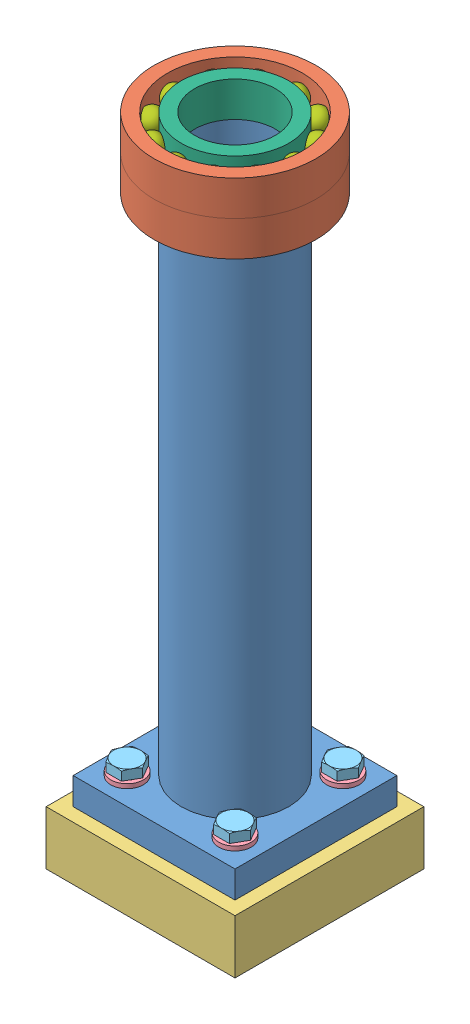
SolidWorks assembly BE101-01Z-02Z 立柱套装, configuration 默认. Lengths in mm.
Overall size (70 243 70).
27 component instances, 7 part files, 12 mates.
Components (placement in the parent):
- BE101-01Z-04Z 烟囱与圈-1: BE101-01Z-04Z 烟囱与圈 [默认] at origin size (60 210 60)
  - BE101-01Z-004 中空立柱-1: BE101-01Z-004 中空立柱 [默认] at origin size (60 210 60)
  - BE101-01Z-006 轴承外圈-1: BE101-01Z-006 轴承外圈 [默认] at (0 193.5 0) size (60 13 60)
- BE101-01Z-005 四眼小板-1: BE101-01Z-005 四眼小板 [默认] at (0 -30 0) size (70 20 70)
- plain washers--product grade c gb-1: plain washers--product grade c gb [GB_FASTENER_WASHER_SMWC 6] at (20 1.6 -20) x (1 0 0) z (0 1 0) size (12 12 1.6)
- hex head bolts-full thread grade c gb-1: hex head bolts-full thread grade c gb [GB_FASTENER_BOLT_HHBFTC M6X20-N] at (20 5.6 -20) x (0 -1 0) z (0 0 1) size (24 11.55 10)
- plain washers--product grade c gb-2: plain washers--product grade c gb [GB_FASTENER_WASHER_SMWC 6] at (20 1.6 20) x (1 0 0) z (0 1 0) size (12 12 1.6)
- plain washers--product grade c gb-3: plain washers--product grade c gb [GB_FASTENER_WASHER_SMWC 6] at (-20 1.6 20) x (1 0 0) z (0 1 0) size (12 12 1.6)
- plain washers--product grade c gb-4: plain washers--product grade c gb [GB_FASTENER_WASHER_SMWC 6] at (-20 1.6 -20) x (1 0 0) z (0 1 0) size (12 12 1.6)
- hex head bolts-full thread grade c gb-2: hex head bolts-full thread grade c gb [GB_FASTENER_BOLT_HHBFTC M6X20-N] at (20 5.6 20) x (0 -1 0) z (0 0 1) size (24 11.55 10)
- hex head bolts-full thread grade c gb-3: hex head bolts-full thread grade c gb [GB_FASTENER_BOLT_HHBFTC M6X20-N] at (-20 5.6 20) x (0 -1 0) z (0 0 1) size (24 11.55 10)
- hex head bolts-full thread grade c gb-4: hex head bolts-full thread grade c gb [GB_FASTENER_BOLT_HHBFTC M6X20-N] at (-20 5.6 -20) x (0 -1 0) z (0 0 1) size (24 11.55 10)
- BE101-01Z-03Z 滚珠轴承-1: BE101-01Z-03Z 滚珠轴承 [默认] at (0 206.5 0) size (60 13 60)
  - BE101-01Z-007 轴承内圈-1: BE101-01Z-007 轴承内圈 [默认] at origin size (40 13 40)
  - BE101-01Z-006 轴承外圈-1: BE101-01Z-006 轴承外圈 [默认] at origin size (60 13 60)
  - BE101-01Z-008 轴承滚珠-1: BE101-01Z-008 轴承滚珠 [默认] at (0 0 -22.5) size (8 8 8)
  - BE101-01Z-008 轴承滚珠-2: BE101-01Z-008 轴承滚珠 [默认] at (11.25 0 -19.4856) x (0.866025 0 0.5) z (-0.5 0 0.866025) size (8 8 8)
  - BE101-01Z-008 轴承滚珠-3: BE101-01Z-008 轴承滚珠 [默认] at (19.4856 0 -11.25) x (0.5 0 0.866025) z (-0.866025 0 0.5) size (8 8 8)
  - BE101-01Z-008 轴承滚珠-4: BE101-01Z-008 轴承滚珠 [默认] at (22.5 0 0) x (0 0 1) z (-1 0 0) size (8 8 8)
  - BE101-01Z-008 轴承滚珠-5: BE101-01Z-008 轴承滚珠 [默认] at (19.4856 0 11.25) x (-0.5 0 0.866025) z (-0.866025 0 -0.5) size (8 8 8)
  - BE101-01Z-008 轴承滚珠-6: BE101-01Z-008 轴承滚珠 [默认] at (11.25 0 19.4856) x (-0.866025 0 0.5) z (-0.5 0 -0.866025) size (8 8 8)
  - BE101-01Z-008 轴承滚珠-7: BE101-01Z-008 轴承滚珠 [默认] at (0 0 22.5) x (-1 0 0) z (0 0 -1) size (8 8 8)
  - BE101-01Z-008 轴承滚珠-8: BE101-01Z-008 轴承滚珠 [默认] at (-11.25 0 19.4856) x (-0.866025 0 -0.5) z (0.5 0 -0.866025) size (8 8 8)
  - BE101-01Z-008 轴承滚珠-9: BE101-01Z-008 轴承滚珠 [默认] at (-19.4856 0 11.25) x (-0.5 0 -0.866025) z (0.866025 0 -0.5) size (8 8 8)
  - BE101-01Z-008 轴承滚珠-10: BE101-01Z-008 轴承滚珠 [默认] at (-22.5 0 0) x (0 0 -1) z (1 0 0) size (8 8 8)
  - BE101-01Z-008 轴承滚珠-11: BE101-01Z-008 轴承滚珠 [默认] at (-19.4856 0 -11.25) x (0.5 0 -0.866025) z (0.866025 0 0.5) size (8 8 8)
  - BE101-01Z-008 轴承滚珠-12: BE101-01Z-008 轴承滚珠 [默认] at (-11.25 0 -19.4856) x (0.866025 0 -0.5) z (0.5 0 0.866025) size (8 8 8)
Mates (geometry in assembly coordinates):
- Coincident1: coincident anti-aligned: plane of BE101-01Z-04Z 烟囱与圈-1/BE101-01Z-004 中空立柱-1 through (0 -10 0) normal (0 -1 0); plane of BE101-01Z-005 四眼小板-1 through (0 -10 0) normal (0 1 0)
- Coincident2: coincident aligned: plane of BE101-01Z-005 四眼小板-1 through (0 -30 0) normal (0 0 1)
- Coincident3: coincident aligned: plane of BE101-01Z-005 四眼小板-1 through (0 -30 0) normal (1 0 0)
- Concentric1: concentric aligned: cylinder of BE101-01Z-04Z 烟囱与圈-1/BE101-01Z-004 中空立柱-1 through (20 0 -20) axis (0 1 0) radius 3.3; cylinder of plain washers--product grade c gb-1 through (20 0 -20) axis (0 1 0) radius 3.3
- Coincident4: coincident anti-aligned: plane of BE101-01Z-04Z 烟囱与圈-1/BE101-01Z-004 中空立柱-1 through (0 0 0) normal (0 1 0); plane of plain washers--product grade c gb-1 through (20 0 -20) normal (0 -1 0)
- Concentric2: concentric aligned: cylinder of BE101-01Z-04Z 烟囱与圈-1/BE101-01Z-004 中空立柱-1 through (20 0 -20) axis (0 1 0) radius 3.3; cylinder of hex head bolts-full thread grade c gb-1 through (20 -18.4 -20) axis (0 1 0) radius 3
- Coincident5: coincident anti-aligned: plane of plain washers--product grade c gb-1 through (20 1.6 -20) normal (0 1 0); plane of hex head bolts-full thread grade c gb-1 through (11.3397 1.6 -25) normal (0 -1 0)
- Concentric3: concentric aligned: cylinder of BE101-01Z-04Z 烟囱与圈-1/BE101-01Z-004 中空立柱-1 through (0 200 0) axis (0 -1 0) radius 20; cylinder of BE101-01Z-03Z 滚珠轴承-1/BE101-01Z-007 轴承内圈-1 through (0 213 0) axis (0 -1 0) radius 15
- Coincident6: coincident anti-aligned: plane of BE101-01Z-04Z 烟囱与圈-1/BE101-01Z-004 中空立柱-1 through (0 200 0) normal (0 1 0); plane of BE101-01Z-03Z 滚珠轴承-1/BE101-01Z-007 轴承内圈-1 through (0 200 0) normal (0 -1 0)
- 重合1: coincident aligned: plane of BE101-01Z-04Z 烟囱与圈-1 through (0 0 0) normal (0 0 1)
- 重合2: coincident aligned: plane of BE101-01Z-04Z 烟囱与圈-1 through (0 0 0) normal (0 1 0)
- 重合3: coincident aligned: plane of BE101-01Z-04Z 烟囱与圈-1 through (0 0 0) normal (1 0 0)
